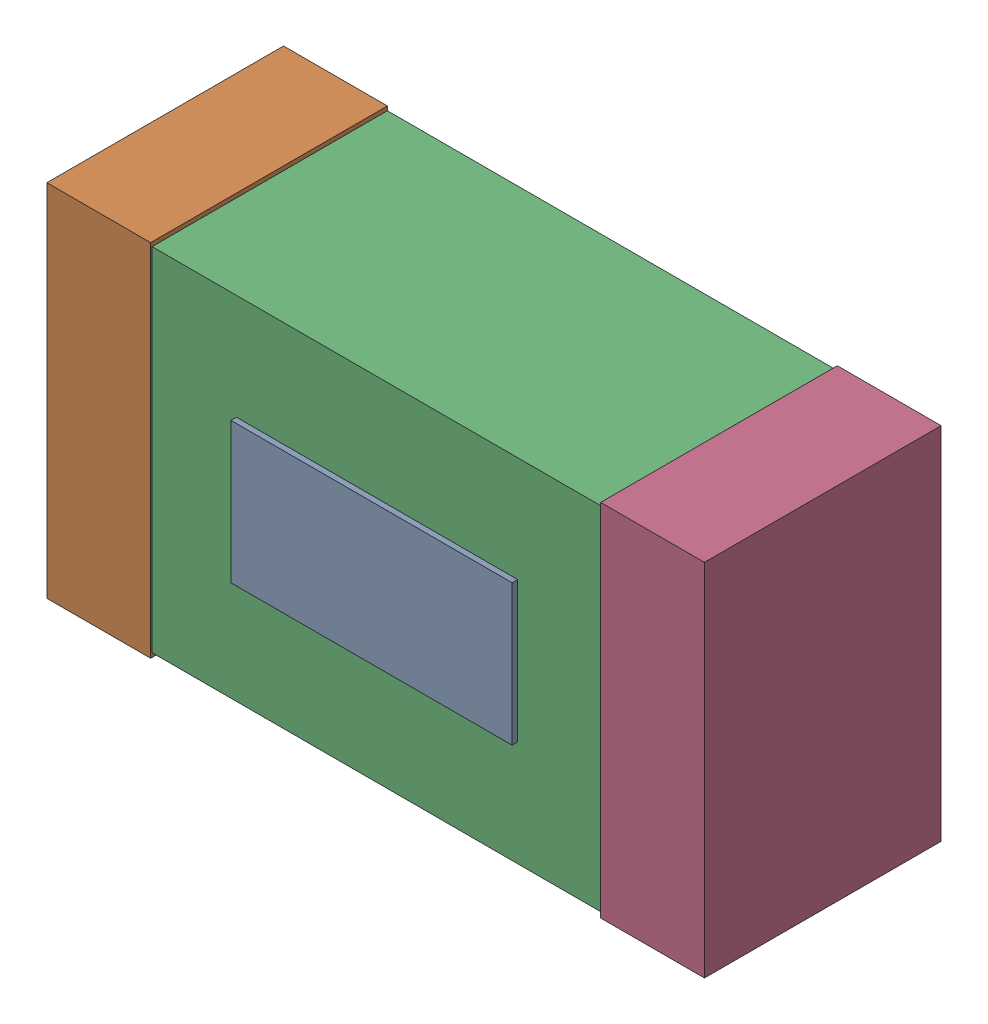
SolidWorks assembly D3, configuration Default. Lengths in mm.
Overall size (2.38 1.3 0.87).
8 component instances, 3 part files, 0 mates.
Components (placement in the parent):
- 384311488-1: 384311488 [Default] at (6.35 67.31 0) size (1.02 0.51 0.87)
  - Extruded_15-1: Extruded_15 [Default] at origin size (1.02 0.51 0.87)
- 384311232-1: 384311232 [Default] at (5.35 67.31 0) size (0.38 1.3 0.85)
  - Extruded_8-1: Extruded_8 [Default] at origin size (0.38 1.3 0.85)
- 384311360-1: 384311360 [Default] at (6.35 67.31 0) size (2.2 1.27 0.85)
  - Extruded_9-1: Extruded_9 [Default] at origin size (2.2 1.27 0.85)
- 384311232-2: 384311232 [Default] at (7.35 67.31 0) size (0.38 1.3 0.85)
  - Extruded_8-1: Extruded_8 [Default] at origin size (0.38 1.3 0.85)
